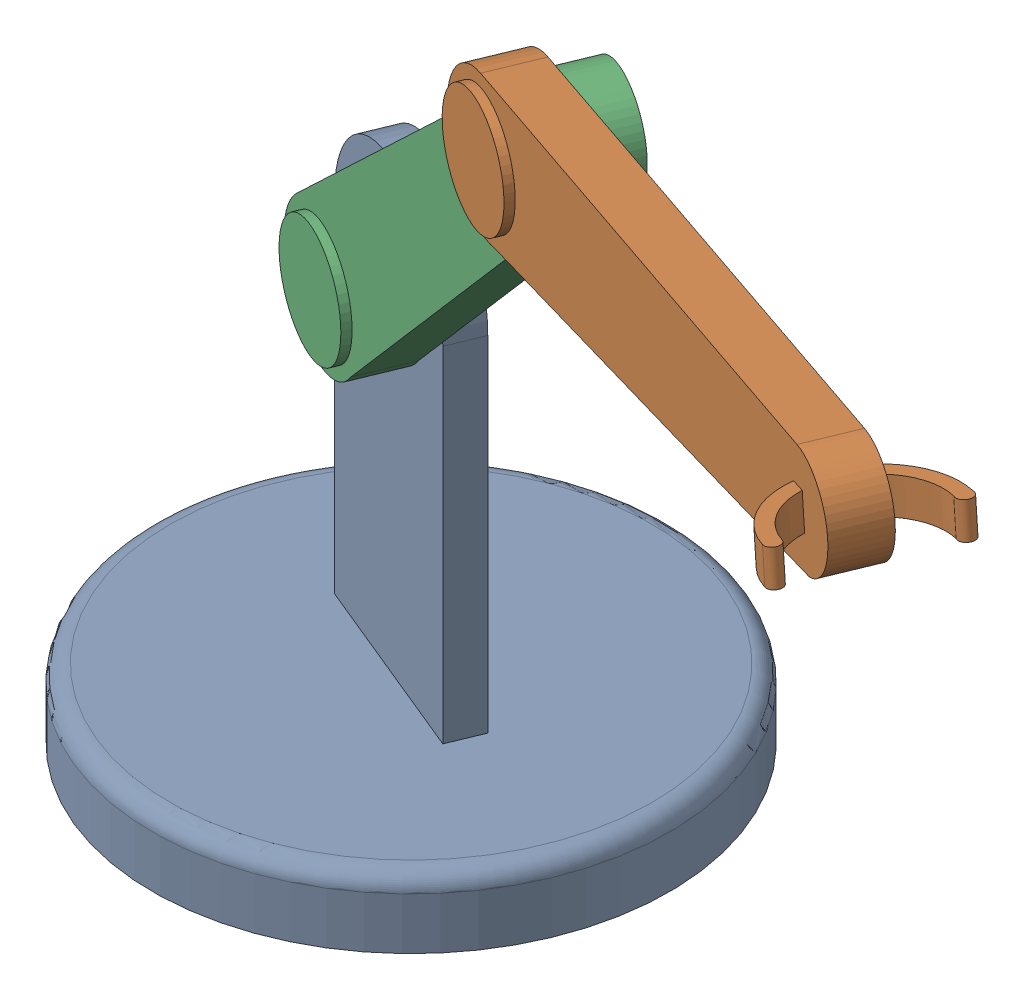
SolidWorks assembly Assem1, configuration Default. Lengths in mm.
Overall size (388.76 281.78 265.69).
3 component instances, 3 part files, 4 mates.
Components (placement in the parent):
- Part1-1: Part1 [Default] at (31.0307 0 89.8203) x (-0.924567 0 -0.381019) z (0.381019 0 -0.924567) size (150 148.96 150)
- Part3-1: Part3 [Default] at (212.3797 248.1325 194.2987) x (0.916818 0.129201 0.377825) z (-0.381019 0 0.924567) size (211.95 40 47.46)
- Part2-1: Part2 [Default] at (83.2167 178.5752 124.8462) x (0.669985 0.68912 0.276104) z (-0.381019 0 0.924567) size (205 40 27.5)
Mates (geometry in assembly coordinates):
- Coincident2: coincident anti-aligned: plane of Part1-1 through (29.1256 0 94.4432) normal (-0.381019 0 0.924567); plane of Part2-1 through (86.0744 178.5752 117.912) normal (0.381019 0 -0.924567)
- Concentric1: concentric aligned: cylinder of Part1-1 through (32.9358 120 85.1975) axis (-0.381019 0 0.924567) radius 5; cylinder of Part2-1 through (32.9358 120 85.1975) axis (-0.381019 0 0.924567) radius 5
- Coincident3: coincident anti-aligned: plane of Part3-1 through (215.2374 248.1325 187.3645) normal (0.381019 0 -0.924567); plane of Part2-1 through (80.3591 178.5752 131.7805) normal (-0.381019 0 0.924567)
- Concentric2: concentric aligned: cylinder of Part3-1 through (141.118 237.1504 146.0037) axis (-0.381019 0 0.924567) radius 5; cylinder of Part2-1 through (141.118 237.1504 146.0037) axis (-0.381019 0 0.924567) radius 5
